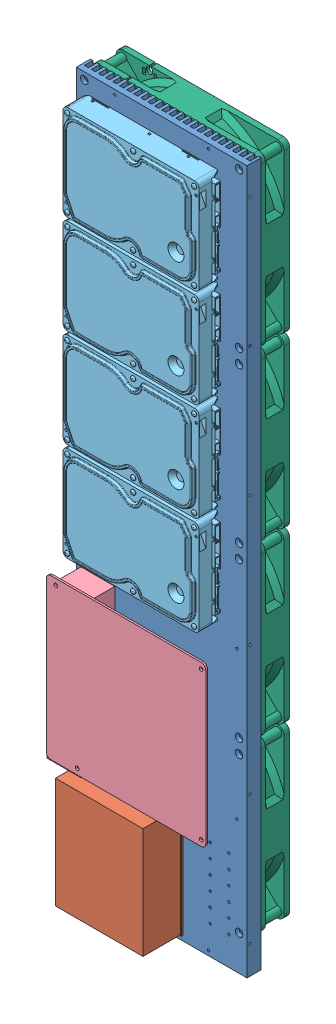
SolidWorks assembly NAS_MAIN_ASSY, configuration 기본. Lengths in mm.
Overall size (182 750 93.6).
12 component instances, 6 part files, 14 mates.
Components (placement in the parent):
- NAS_HEATSINK-1: NAS_HEATSINK [기본] at origin size (182 750 15)
- MICRONIX_SFX300-1: MICRONIX_SFX300 [기본] at (-20 70 5) size (95.3 120 41.6)
- NAS_BLOCK-1: NAS_BLOCK [기본] at origin size (35 35 28.5)
- ASROCK_A520M-ITX-1: ASROCK_A520M-ITX [기본] at (0 220 38) x (1 0 0) z (0 1 0) size (171 38 172.62)
- HDD-1: HDD [기본] at (-10 365 0) x (0 1 0) z (1 0 0) size (101.5 25.96 145.2)
- HDD-2: HDD [기본] at (-10 470 0) x (0 1 0) z (1 0 0) size (101.5 25.96 145.2)
- Silverstone_AP181-1: Silverstone_AP181 [기본] at (0 120 -31) x (0 -1 0) z (-1 0 0) size (179 32 179)
- Silverstone_AP181-2: Silverstone_AP181 [기본] at (0 300 -31) x (0 -1 0) z (-1 0 0) size (179 32 179)
- Silverstone_AP181-3: Silverstone_AP181 [기본] at (0 480 -31) x (0 -1 0) z (-1 0 0) size (179 32 179)
- Silverstone_AP181-4: Silverstone_AP181 [기본] at (0 660 -31) x (0 -1 0) z (-1 0 0) size (179 32 179)
- HDD-5: HDD [기본] at (-10 575 0) x (0 1 0) z (1 0 0) size (101.5 25.96 145.2)
- HDD-6: HDD [기본] at (-10 680 0) x (0 1 0) z (1 0 0) size (101.5 25.96 145.2)
Mates (geometry in assembly coordinates):
- 일치8: coincident aligned: plane of NAS_HEATSINK-1 through (-91 750 0) normal (0 0 1); plane of HDD_SATA_3.5-1 through (-10 365 0) normal (0 0 1)
- 일치9: coordinate: point of NAS_HEATSINK-1
- 거리6: distance = 10 mm aligned: plane of HDD_SATA_3.5-1 through (-10 365 0) normal (1 0 0)
- 거리7: distance = 365 mm aligned: plane of HDD_SATA_3.5-1 through (-10 365 0) normal (0 1 0)
- 일치16: coordinate: unknown of NAS_BLOCK-1
- 동심2: concentric aligned: cylinder of NAS_HEATSINK-1 through (-82.5 202.5 0) axis (0 0 1) radius 2.25; cylinder of Silverstone_AP181-1 through (-82.5 202.5 -47) axis (0 0 1) radius 2.25
- 거리9: distance = 36 mm anti-aligned: plane of ASROCK_A520M-ITX-1 through (0 220 36) normal (0 0 -1); plane of NAS_HEATSINK-1 through (-91 750 0) normal (0 0 1)
- 일치19: coincident aligned: plane of NAS_HEATSINK-1 through (0 0 0) normal (1 0 0); plane of ASROCK_A520M-ITX-1 through (0 220 38) normal (1 0 0)
- 거리10: distance = 220 mm aligned: plane of NAS_HEATSINK-1 through (0 0 0) normal (0 1 0); plane of ASROCK_A520M-ITX-1 through (0 220 38) normal (0 1 0)
- 거리11: distance = 5 mm anti-aligned: plane of MICRONIX_SFX300-1 through (-20 70 5) normal (0 0 -1); plane of NAS_HEATSINK-1 through (-91 750 0) normal (0 0 1)
- 거리12: distance = 20 mm aligned: plane of NAS_HEATSINK-1 through (0 0 0) normal (1 0 0); plane of MICRONIX_SFX300-1 through (-20 70 5) normal (1 0 0)
- 거리13: distance = 70 mm aligned: plane of MICRONIX_SFX300-1 through (-20 70 5) normal (0 1 0); plane of NAS_HEATSINK-1 through (0 0 0) normal (0 1 0)
- 동심3: concentric aligned: cylinder of NAS_HEATSINK-1 through (82.5 37.5 0) axis (0 0 1) radius 2.25; cylinder of Silverstone_AP181-1 through (82.5 37.5 -47) axis (0 0 1) radius 2.25
- 일치20: coincident anti-aligned: plane of NAS_HEATSINK-1 through (-91 750 -15) normal (0 0 -1); plane of Silverstone_AP181-1 through (0 255 -15) normal (0 0 1)
